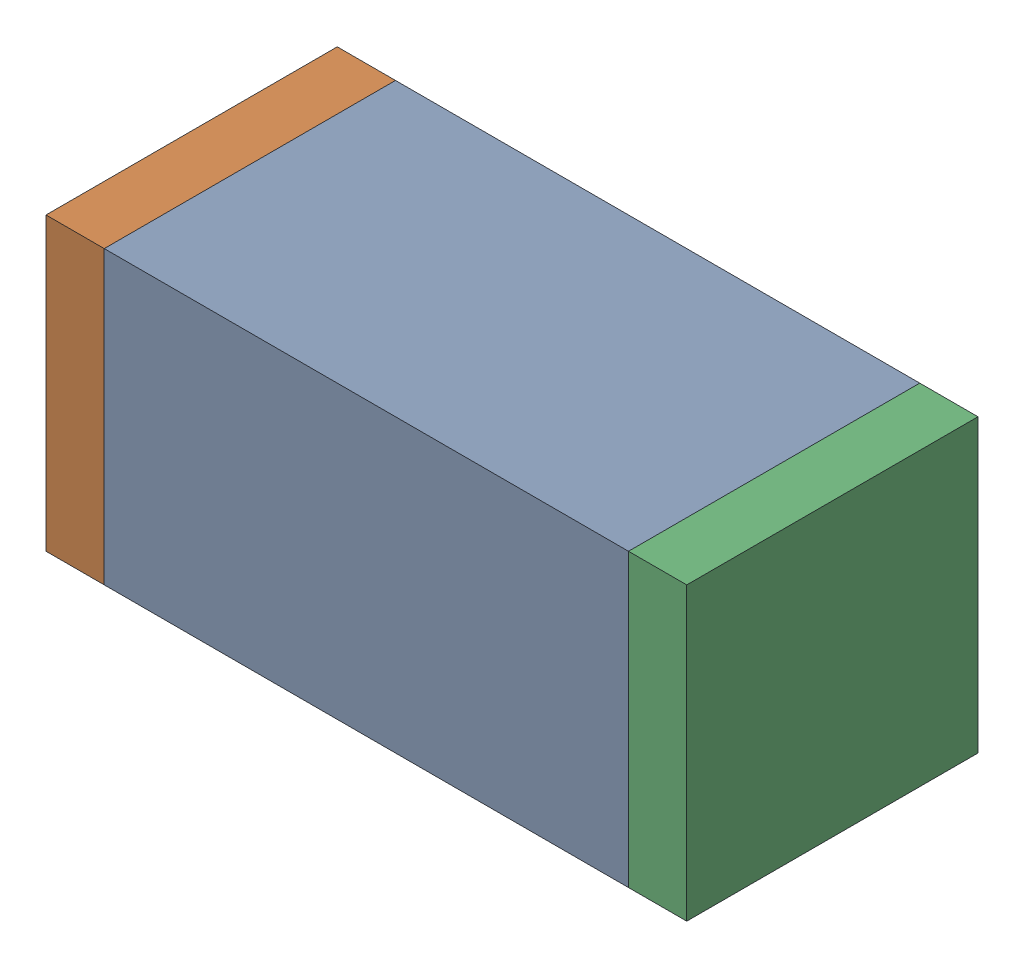
SolidWorks assembly C53, configuration Default. Lengths in mm.
Overall size (1.1 0.5 0.5).
6 component instances, 2 part files, 0 mates.
Components (placement in the parent):
- 836749680-1: 836749680 [Default] at (113.95 45.15 0) size (0.9 0.5 0.5)
  - Extruded_4-1: Extruded_4 [Default] at origin size (0.9 0.5 0.5)
- 810156080-1: 810156080 [Default] at (113.45 45.15 0) size (0.1 0.5 0.5)
  - Extruded_5-1: Extruded_5 [Default] at origin size (0.1 0.5 0.5)
- 810156080-2: 810156080 [Default] at (114.45 45.15 0) size (0.1 0.5 0.5)
  - Extruded_5-1: Extruded_5 [Default] at origin size (0.1 0.5 0.5)
